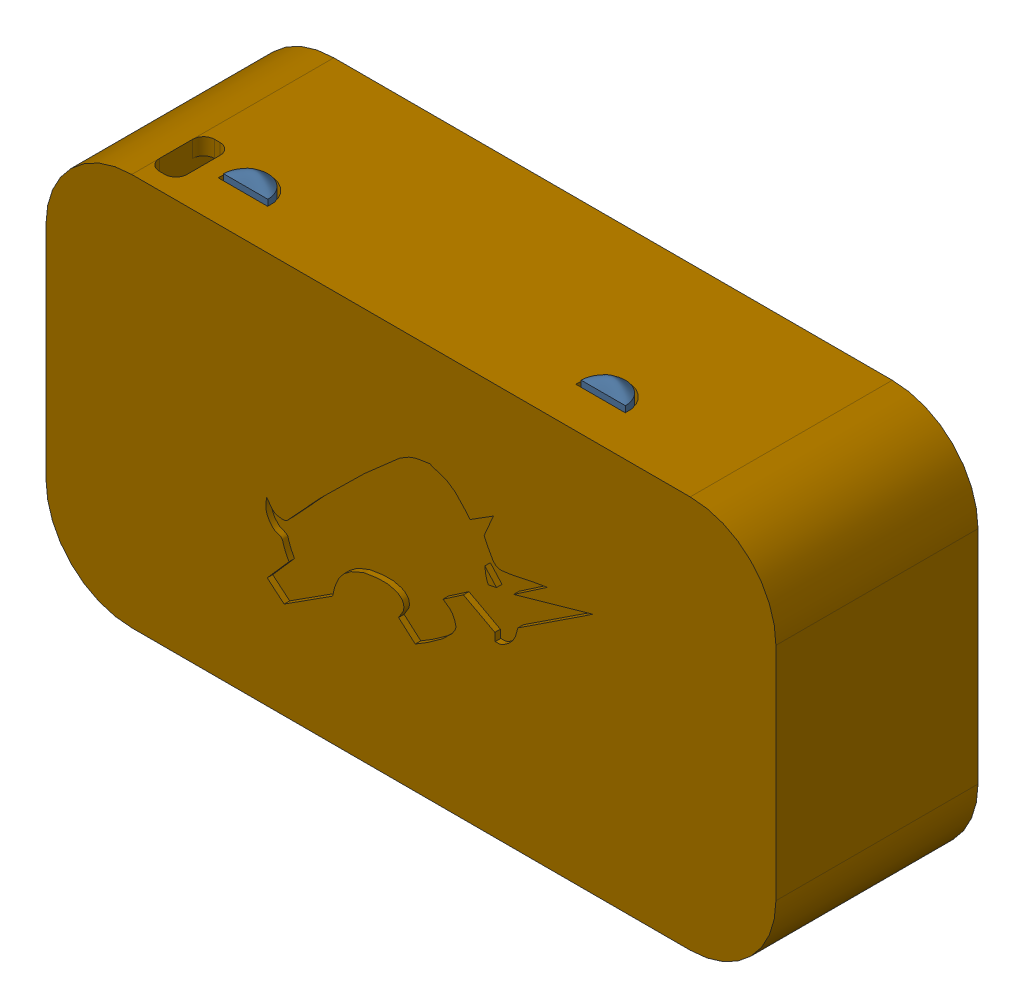
SolidWorks assembly Full Assembly, configuration Default. Lengths in mm.
Overall size (67.06 37.36 18.57).
13 component instances, 10 part files, 19 mates.
Components (placement in the parent):
- PCB Assembly-1: PCB Assembly [Default] at (3.26 -2.96 9.525) x (0 1 0) z (0 0 1) size (32.15 45 5.74)
  - Mainboard-1: Mainboard [Default] at (13.55 -45 2.54) x (-1 0 0) z (0 0 -1) size (27.1 45 2.54)
  - BLE Module-1: BLE Module [Default] at (8.975 -11.7 3.74) x (-1 0 0) z (0 1 0) size (18 3.2 10)
  - Tactile Switch PTS840-2: Tactile Switch PTS840 [Default] at (13.55 -3 3.89) x (0 1 0) z (1 0 0) size (3.5 1.35 3.55)
  - Tactile Switch PTS840-3: Tactile Switch PTS840 [Default] at (13.55 -35.85 3.89) x (0 1 0) z (1 0 0) size (3.5 1.35 3.55)
  - RGB LED-1: RGB LED [Default] at (2.225 -1.25 3.54) x (1 0 0) z (0 1 0) size (3.2 1 1.5)
  - USB Connector micro B smd-1: USB Connector micro B smd [Default] at (-8.675 -8.375 2.54) x (0 -1 0) z (-1 0 0) size (7.8 2.45 5.5)
  - MPU-6050-1: MPU-6050 [Default] at (6.262 -38.142 2.54) x (1 0 0) z (0 -1 0) size (4 0.9 4)
- LIPO 1S 1000mAh-1: LIPO 1S 1000mAh [Default] at (25.4 0 0) x (0 1 0) z (0 0 1) size (33.02 50.8 9.53)
- Vibration motor-1: Vibration motor [Default] at (-3.508 9.3904 3.762) x (-0.560651 0 0.828052) z (0.828052 0 0.560651) size (6 17.22 6)
- Main Enclosure-1: Main Enclosure [Default] at (25.4 0 0) x (0 -1 0) z (0 0 -1) size (36.07 67.06 18.57)
- Volume Button-1: Volume Button [Default] at (3.0824 11.24 9.525) x (1 0 0) z (0 -1 0) size (6.35 3.83 11.89)
- Volume Button-2: Volume Button [Default] at (35.9324 11.24 9.525) x (1 0 0) z (0 -1 0) size (6.35 3.83 11.89)
Mates (geometry in assembly coordinates):
- Coincident1: coincident anti-aligned: plane of PCB Assembly-1/Mainboard-1 through (48.26 10.59 9.525) normal (0 0 -1); plane of LIPO 1S 1000mAh-1 through (25.4 0 9.525) normal (0 0 1)
- Coincident15: coincident aligned: plane of PCB Assembly-1/Mainboard-1 through (48.26 -16.51 9.525) normal (0 -1 0); plane of LIPO 1S 1000mAh-1 through (0 -16.51 9.525) normal (0 -1 0)
- Distance2: distance = 2.54 mm aligned: plane of PCB Assembly-1/Mainboard-1 through (48.26 10.59 9.525) normal (1 0 0); plane of LIPO 1S 1000mAh-1 through (50.8 16.51 9.525) normal (1 0 0)
- Coincident20: coincident aligned: plane of LIPO 1S 1000mAh-1; plane of assembly through (0 0 0) normal (0 1 0)
- Coincident21: coincident anti-aligned: plane of LIPO 1S 1000mAh-1 through (0 16.51 9.525) normal (-1 0 0); plane of assembly through (0 0 0) normal (1 0 0)
- Coincident22: coincident anti-aligned: plane of LIPO 1S 1000mAh-1 through (25.4 0 0) normal (0 0 -1); plane of assembly through (0 0 0) normal (0 0 1)
- Distance6: distance = 0.508 mm anti-aligned: cylinder of Vibration motor-1 through (-3.508 -2.5476 3.762) axis (0 1 0) radius 3; plane of LIPO 1S 1000mAh-1 through (0 16.51 9.525) normal (-1 0 0)
- Distance5: distance = 0.762 mm aligned: plane of LIPO 1S 1000mAh-1 through (25.4 0 0) normal (0 0 -1); cylinder of Vibration motor-1 through (-3.508 -2.5476 3.762) axis (0 1 0) radius 3
- InPlace2: in place: plane of LIPO 1S 1000mAh-1 through (25.4 0 0) normal (0 0 -1); plane of ? through (0 0 0) normal (0 0 -1); moOrthogonalPlaneRef_w of LIPO 1S 1000mAh-1 through (25.4 0 0) normal (0 0 -1); unknown of ?; plane of LIPO 1S 1000mAh-1 through (25.4 0 0) normal (0 0 -1); plane of ? through (0 0 0) normal (-1 0 0); plane of LIPO 1S 1000mAh-1 through (25.4 0 0) normal (0 0 -1); unknown of Main Enclosure-1
- Coincident27: coincident aligned: plane of LIPO 1S 1000mAh-1; plane of Main Enclosure-1
- Coincident28: coincident aligned: moOrthogonalPlaneRef_w of LIPO 1S 1000mAh-1 through (25.4 0 0) normal (-1 0 0); plane of Main Enclosure-1
- Coincident29: coincident anti-aligned: moOrthogonalPlaneRef_w of LIPO 1S 1000mAh-1 through (25.4 0 0) normal (0 1 0); plane of Main Enclosure-1
- Coincident30: coincident anti-aligned: plane of PCB Assembly-1/Tactile Switch PTS840-2 through (6.26 11.24 13.415) normal (0 1 0); plane of Volume Button-1 through (3.0824 11.24 9.525) normal (0 -1 0)
- Distance7: distance = 0.1524 mm anti-aligned: plane of PCB Assembly-1/Tactile Switch PTS840-2 through (8.01 7.69 13.415) normal (1 0 0); plane of Volume Button-1 through (8.1624 7.43 13.335) normal (-1 0 0)
- Coincident32: coincident anti-aligned: plane of LIPO 1S 1000mAh-1 through (25.4 0 9.525) normal (0 0 1); plane of Volume Button-1 through (3.0824 15.812 9.525) normal (0 0 -1)
- Coincident33: coincident anti-aligned: plane of PCB Assembly-1/Tactile Switch PTS840-3 through (39.11 11.24 13.415) normal (0 1 0); plane of Volume Button-2 through (35.9324 11.24 9.525) normal (0 -1 0)
- Coincident34: coincident anti-aligned: plane of LIPO 1S 1000mAh-1 through (25.4 0 9.525) normal (0 0 1); plane of Volume Button-2 through (35.9324 15.812 9.525) normal (0 0 -1)
- Distance8: distance = 0.1524 mm anti-aligned: plane of PCB Assembly-1/Tactile Switch PTS840-3 through (40.86 7.69 13.415) normal (1 0 0); plane of Volume Button-2 through (41.0124 7.43 13.335) normal (-1 0 0)
- Parallel1: parallel anti-aligned: plane of LIPO 1S 1000mAh-1 through (0 -16.51 9.525) normal (0 -1 0); plane of Vibration motor-1 through (-3.508 9.3904 3.762) normal (0 1 0)
